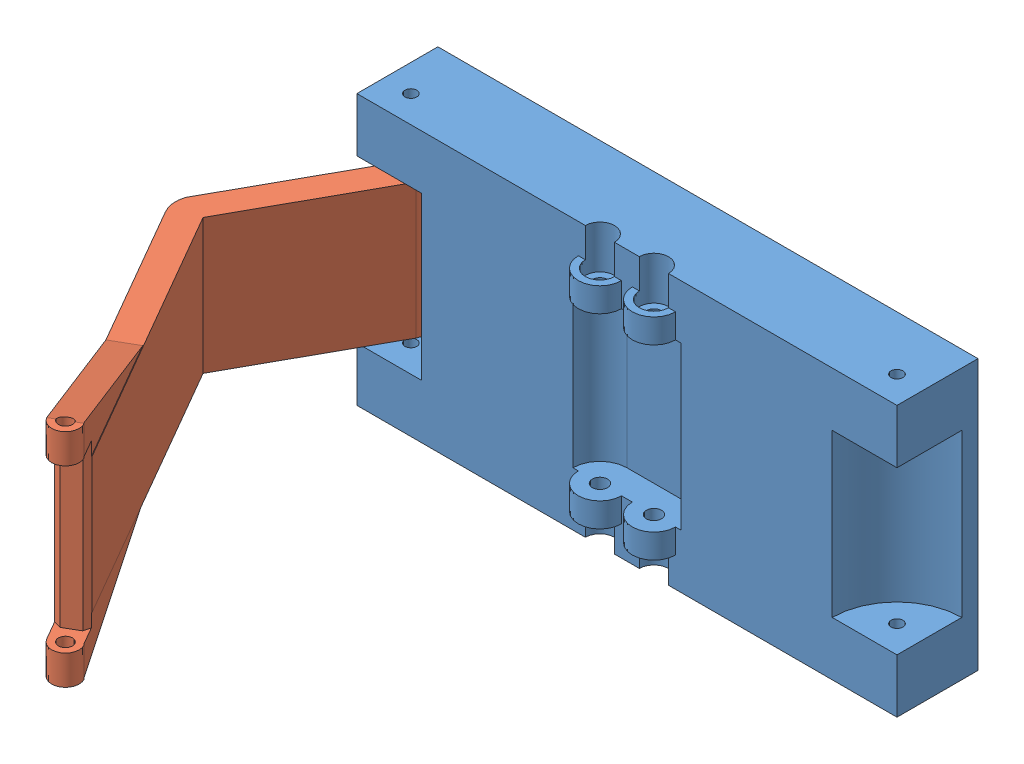
SolidWorks assembly turn_moving_1_0, configuration 默认. Lengths in mm.
Overall size (128.54 50 93.36).
2 component instances, 2 part files, 2 mates.
Components (placement in the parent):
- base-1: base [默认] at (19.3575 -19.0034 208) size (100 50 19)
- hand-1: hand [默认] at (-25.6425 -6.5034 210.5) x (0.874883 0 0.484334) z (-0.484334 0 0.874883) size (57.69 41 67.23)
Mates (geometry in assembly coordinates):
- 同心1: concentric aligned: circle of base-1; circle of hand-1
- 距离1: distance = 2.5 mm anti-aligned: plane of hand-1 through (-25.6425 18.4966 210.5) normal (0 1 0); plane of base-1 through (19.3575 20.9966 215.5) normal (0 -1 0)
